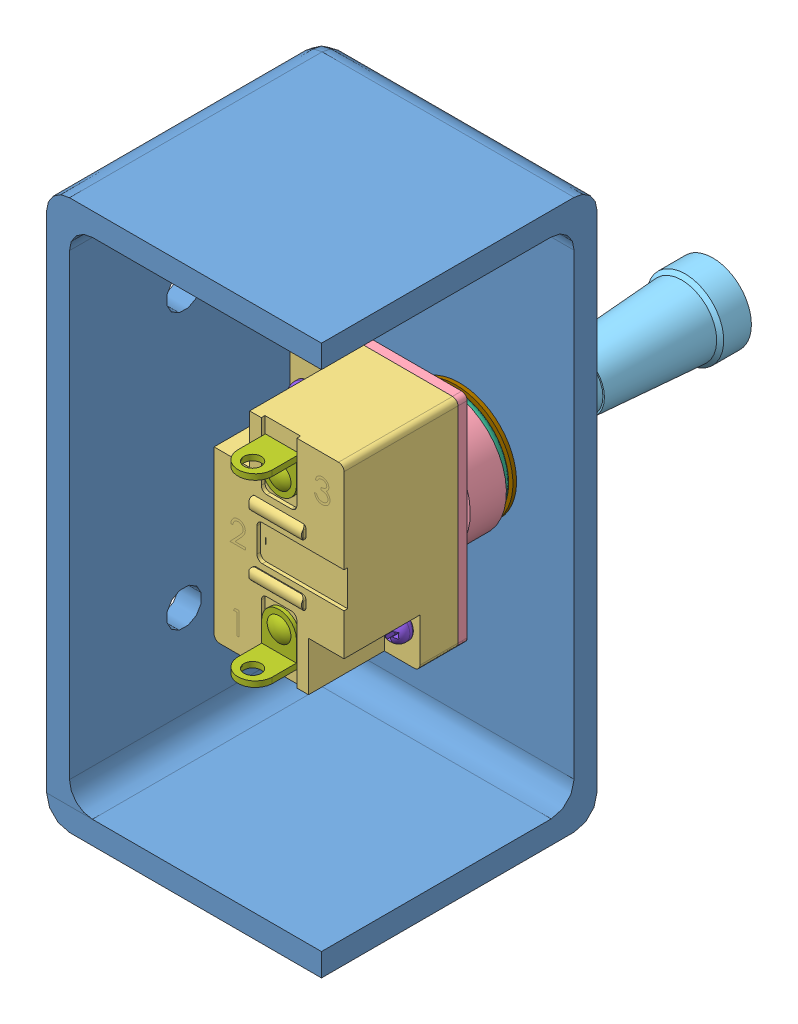
SolidWorks assembly NUC WEAP Switch, configuration Default. Lengths in mm.
Overall size (38.1 93.31 87.34).
15 component instances, 13 part files, 6 mates.
Components (placement in the parent):
- NUC WEAP Switch-1: NUC WEAP Switch [Default] at (38.1 -3027.3027 -1180.9641) x (0 0.241922 -0.970296) z (1 0 0) size (54.82 82.5 38.1)
- NUC WEAP Placard-1: NUC WEAP Placard [Default] x (-1 0 0) z (0 0 -1) size (21.47 41.27 0.13)
- SxAL-1: SxAL [S1AL - Round Bat] at (22.225 -38.1 12.3952) x (1 0 0) z (0 1 0) size (18.01 65.15 30)
  - S2AL_SMC_body1-body-1: S2AL_SMC_body1-body [Default] at origin size (18.01 16.36 30)
  - S2AL_SMC_plate13-1: S2AL_SMC_plate13 [Default] at origin size (18.01 21.39 30)
  - S2AL_S2AL_bat-1: S2AL_S2AL_bat [Removed Bat] at (0 14.7066 0) size (7.39 24.87 7.39)
  - S2AL_AT537-1: S2AL_AT537 [Default] at (0 7.9629 0) x (1 0 0) z (0 -1 0) size (15.49 15.49 1.5)
  - S2AL_SMC_trmnls2-terminals-1: S2AL_SMC_trmnls2-terminals [Default] at (0 -15.0114 0) size (16.2 6.6 44.08)
  - S2AL_M2_5x7_5-1: S2AL_M2_5x7_5 [Default] at (6.4643 -5.2832 -10.541) x (1 0 0) z (0 -1 0) size (3.56 3.56 9.47)
  - S2AL_M2_5x7_5-2: S2AL_M2_5x7_5 [Default] at (-6.4643 -5.2832 10.541) x (1 0 0) z (0 -1 0) size (3.56 3.56 9.47)
  - S2AL_AT508-1: S2AL_AT508 [Default] at (0 8.9662 0) x (1 0 0) z (0 -1 0) size (15.8 15.8 0.51)
  - S2AL_AT503M-1: S2AL_AT503M [Default] at (0 12.0396 0) x (1 0 0) z (0 1 0) size (16 14 2.4)
  - Tall Locking Bat-1: Tall Locking Bat [Default] at origin (suppressed, hidden)
  - Conical Locking Bat-1: Conical Locking Bat [Default] x (0 0 -1) z (1 0 0) (suppressed, hidden)
  - Round Locking Bat-1: Round Locking Bat [Default] x (0 0 -1) z (1 0 0) size (10.54 18.26 10.54)
Mates (geometry in assembly coordinates):
- Coincident1: coincident anti-aligned: plane of NUC WEAP Switch-1 through (0 -71.4475 3.2543) normal (-1 0 0); plane of assembly through (0 0 0) normal (1 0 0)
- Coincident2: coincident aligned: plane of NUC WEAP Switch-1 through (-99.9844 0 38.1893) normal (0 1 0); plane of assembly through (0 0 0) normal (0 1 0)
- Coincident3: coincident anti-aligned: plane of NUC WEAP Switch-1 through (-99.9844 0 0) normal (0 0 -1); plane of assembly through (0 0 0) normal (0 0 1)
- Concentric1: concentric aligned: cylinder of NUC WEAP Switch-1 through (22.225 -38.1 0) axis (0 0 -1) radius 6.35; cylinder of SxAL-1/S2AL_SMC_plate13-1 through (22.225 -38.1 11.4554) axis (0 0 -1) radius 8.4963
- Coincident4: coincident anti-aligned: plane of NUC WEAP Switch-1 through (-99.9844 0 3.175) normal (0 0 1); plane of SxAL-1/S2AL_AT508-1 through (22.225 -38.1 3.175) normal (0 0 -1)
- Parallel1: parallel aligned: plane of NUC WEAP Switch-1 through (38.1 -3027.3027 -1180.9641) normal (1 0 0); plane of SxAL-1/S2AL_SMC_body1-body-1 through (31.2293 -23.8633 28.194) normal (1 0 0)
